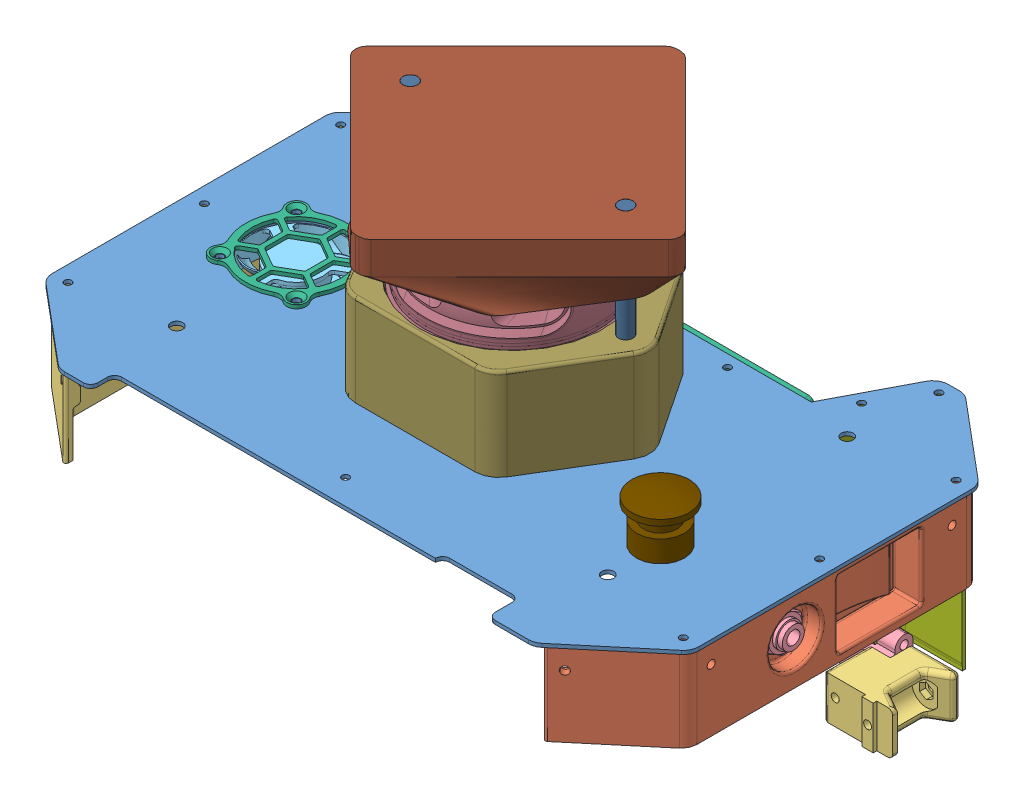
SolidWorks assembly BlocSup, configuration Défaut. Lengths in mm.
Overall size (270 207.07 197.32).
32 component instances, 28 part files, 65 mates.
Components (placement in the parent):
- BlocSup_Plaque-1: BlocSup_Plaque [Défaut] at (0 343.5 0) x (0 0 -1) z (1 0 0) size (180 1.5 270)
- BlocSup_CarterGauche-1: BlocSup_CarterGauche [Défaut] at (135 295.5187 -42.1103) x (0 0 -1) z (1 0 0) size (173.26 35 33.94)
- BlocSup_CarterDroite-1: BlocSup_CarterDroite [Défaut] at (-135 308.5 0) x (0 0 1) z (-1 0 0) size (173.26 35 33.94)
- BlocSup_Charniere-1: BlocSup_Charniere [Défaut] at (0 238 -83.5) x (0 0 -1) z (1 0 0) size (10 17.5 158)
- BlocSup_SupportCharniere-1: BlocSup_SupportCharniere [Défaut] at (-90 227.5 -50) x (-1 0 0) z (0 0 -1) size (29 18 30)
- BlocSup_SupportEcran-1: BlocSup_SupportEcran [Défaut] at (0 292.3655 -56.8959) x (-1 0 0) z (0 0.32983 -0.94404) size (138 106.19 17.63)
- BlocSup_CarterEcran-1: BlocSup_CarterEcran [Défaut] at (70.0918 245.5 -90) x (-1 0 0) z (0 0 -1) size (29.48 98 45)
- _Symétrie_BlocSup_CarterEcran-1: _Symétrie_BlocSup_CarterEcran [Défaut] at (-70.0918 245.5 -90) size (29.48 98 45.96)
- Lidar-1: Lidar [Default] at (0 345 0) size (135.87 85 134.45)
  - Lidar_Base-1: Lidar_Base [Défaut] at origin size (105 35.5 75)
  - Lidar_Tige-1: Lidar_Tige [Défaut] at (-45 5 -2.5) size (6 80 6)
  - Lidar_Tige-2: Lidar_Tige [Défaut] at (45 5 -2.5) size (6 80 6)
  - Lidar_Top-1: Lidar_Top [Défaut] at (0 85 -2.5) x (-1 0 0) z (0 0 1) size (135.87 27.01 134.45)
  - Lidar_Cache-1: Lidar_Cache [Défaut] at (0 38.3 -2.5) x (-1 0 0) z (0 0 1) size (110 38.3 83)
  - rplidar-a2-1: rplidar-a2 [Défaut] at (-75 9.2861 -6.0269) x (0 0 -1) z (1 0 0) size (80.61 40.81 84.84)
- Tirette-1: Tirette [Défaut] at (15.8155 -23.9188 -0.5) size (18.01 65.48 50.46)
  - TiretteDiam6-1: TiretteDiam6 [Default] at (-106.1573 340.7878 -102.5731) x (-0.007647 0.642769 0.766022) z (0 -0.766044 0.642788) size (6 6 61)
  - Tirette_Support-1: Tirette_Support [Défaut] at (-106.1573 276.0497 -60) x (0 0 1) z (-1 0 0) size (28.63 58.34 18.1)
  - microswitchGaletAss-1: microswitchGaletAss [Défaut] at (-106.1573 330.3845 -72.9571) x (0 -0.766044 0.642788) z (1 0 0) size (21.06 21.1 7)
    - microswitchGalet02-1: microswitchGalet02 [Défaut] at origin size (20 15 7)
    - microswitchGalet01-1: microswitchGalet01 [Défaut] at (1.7099 12.1145 0) x (0.996636 -0.081957 0) z (0 0 1) size (19 9 6)
- APEM_A01ES_A0154B-1: APEM_A01ES_A0154B [Défaut] at (90 345 28) size (24 61 24)
- Ecran_5po_DFR0550-1: Ecran_5po_DFR0550 [Default] at (0 297.1481 -70.5845) x (1 0 0) z (0 0.32983 -0.94404) size (121 76 27.3)
- interrupteur principal-1: interrupteur principal [Défaut] at (121.5 326 -20) x (0 0 1) z (0 1 0) size (32 33.35 25)
- _Symétrie_BlocSup_SupportCharniere-3: _Symétrie_BlocSup_SupportCharniere [Défaut] at (90 227.5 -50) size (29 18 30)
- PriseJackAlim-1: PriseJackAlim [Default] at (123.5 326 15) x (0 -1 0) z (0 0 1) size (16.17 25.3 16)
- Ventilo_AAB_Diam40-1: Ventilo_AAB_Diam40 [Défaut] at (-90 333.5 0) x (1 0 0) z (0 1 0) size (45 40 10)
- Ventilo_Cache-1: Ventilo_Cache [Défaut] at (-90 345 0) x (0 0 -1) z (1 0 0) size (42.6 1.5 42.6)
- Raspberry-Pi-4-Model-B-03-1: Raspberry-Pi-4-Model-B-03 [Défaut] at (-32.5 266.2952 -67.1696) x (1 0 0) z (0 -0.32983 0.94404) size (87.94 57.9 19.63)
- InterfaceRaspi-1: InterfaceRaspi [Défaut] at (-107.5 400.9752 -9.9988) x (1 0 0) z (0 -0.32983 0.94404) size (65 56 17.8)
- 4010 - Blower Assembly-1: 4010 - Blower Assembly [Défaut] at (19.1478 275.9461 -78.4041) x (-1 0 0) z (0 -0.32983 0.94404) size (40 40 9.75)
- Ventilo_Raspi_Support-1: Ventilo_Raspi_Support [Défaut] at (0 270.259 -67.9033) x (-1 0 0) z (0 0.94404 0.32983) size (64 15.5 14.5)
Mates (geometry in assembly coordinates):
- Coïncidente93: coincident: plane of assembly; plane of assembly; plane of BlocSup_Plaque-1 through (0 345 0) normal (0 1 0); plane of APEM_A01ES_A0154B-1 through (100 345 28) normal (0 -1 0)
- Coaxiale32: concentric: cylinder of assembly; cylinder of assembly; cylinder of BlocSup_Plaque-1 through (90 343.5 28) axis (0 1 0) radius 8.15; cylinder of APEM_A01ES_A0154B-1 through (90 364 28) axis (0 -1 0) radius 8
- Coïncidente164: coincident: plane of assembly; plane of assembly; plane of BlocSup_Plaque-1 through (0 343.5 0) normal (0 -1 0); plane of BlocSup_CarterEcran-1 through (88.4018 343.5 -90) normal (0 1 0)
- Coïncidente183: coincident: plane of assembly; plane of assembly; plane of BlocSup_Plaque-1 through (135 345 -90) normal (0 0 -1); plane of BlocSup_CarterEcran-1 through (70.0918 245.5 -90) normal (0 0 -1)
- Coïncidente174: coincident: plane of assembly; plane of assembly; plane of BlocSup_Plaque-1 through (0 343.5 0) normal (0 -1 0); plane of BlocSup_CarterGauche-1 through (135 343.5 0) normal (0 1 0)
- Coïncidente178: coincident: plane of assembly; plane of assembly; plane of BlocSup_Plaque-1 through (0 343.5 0) normal (0 -1 0); plane of BlocSup_CarterDroite-1 through (-135 343.5 0) normal (0 1 0)
- Coaxiale43: concentric: cylinder of assembly; cylinder of assembly; cylinder of BlocSup_Charniere-1 through (79 246.75 -84.75) axis (-1 0 0) radius 1.75; cylinder of BlocSup_SupportEcran-1 through (-48.5 246.75 -84.75) axis (1 0 0) radius 1.75
- Largeur9: width: plane of assembly; plane of assembly; plane of assembly; plane of assembly; plane of BlocSup_Charniere-1 through (-15 238 -83.5) normal (-1 0 0); plane of BlocSup_Charniere-1 through (15 238 -83.5) normal (1 0 0); plane of BlocSup_SupportEcran-1 through (-15.5 292.3655 -56.8959) normal (1 0 0); plane of BlocSup_SupportEcran-1 through (15.5 292.3655 -56.8959) normal (-1 0 0)
- Coïncidente176: coincident: plane of assembly; plane of assembly; plane of interrupteur principal-1 through (121.5 326 -20) normal (-1 0 0); plane of BlocSup_CarterGauche-1 through (121.5 295.5187 -42.1103) normal (1 0 0)
- Largeur18: width: plane of assembly; plane of assembly; plane of assembly; plane of assembly; plane of BlocSup_CarterGauche-1 through (121.5 295.5187 -2.5) normal (0 0 -1); plane of BlocSup_CarterGauche-1 through (121.5 295.5187 -37.5) normal (0 0 1); plane of interrupteur principal-1 through (104.5 315 -34.5) normal (0 0 -1); plane of interrupteur principal-1 through (104.5 315 -5.5) normal (0 0 1)
- Largeur19: width: plane of assembly; plane of assembly; plane of assembly; plane of assembly; plane of interrupteur principal-1 through (104.5 337 -34.5) normal (0 1 0); plane of interrupteur principal-1 through (104.5 315 -34.5) normal (0 -1 0); plane of BlocSup_CarterGauche-1 through (121.5 340 -42.1103) normal (0 -1 0); plane of BlocSup_CarterGauche-1 through (121.5 312 -42.1103) normal (0 1 0)
- Coïncidente184: coincident: plane of assembly; plane of assembly; plane of BlocSup_Plaque-1 through (0 343.5 0) normal (0 -1 0); plane of _Symétrie_BlocSup_CarterEcran-1 through (-88.4018 343.5 -90) normal (0 1 0)
- Coaxiale48: concentric: cylinder of assembly; cylinder of assembly; cylinder of BlocSup_Plaque-1 through (-93.3098 343.5 -85) axis (0 1 0) radius 1.5; cylinder of _Symétrie_BlocSup_CarterEcran-1 through (-93.3098 343.5 -85) axis (0 1 0) radius 1.7
- Parallèle2: parallel: plane of assembly; plane of assembly; plane of BlocSup_Plaque-1 through (-135 345 -90) normal (0 0 -1); plane of _Symétrie_BlocSup_CarterEcran-1 through (-70.0918 245.5 -90) normal (0 0 -1)
- Coaxiale51: concentric: cylinder of assembly; cylinder of assembly; cylinder of BlocSup_Plaque-1 through (93.3098 343.5 -85) axis (0 1 0) radius 1.5; cylinder of BlocSup_CarterEcran-1 through (93.3098 343.5 -85) axis (0 1 0) radius 1.7
- Coaxiale52: concentric: cylinder of assembly; cylinder of assembly; cylinder of BlocSup_Plaque-1 through (128.5 343.5 56.969) axis (0 1 0) radius 1.5; cylinder of BlocSup_CarterGauche-1 through (128.5 343.5 56.969) axis (0 1 0) radius 2
- Coaxiale53: concentric: cylinder of assembly; cylinder of assembly; cylinder of BlocSup_Plaque-1 through (128.5 343.5 -56.969) axis (0 1 0) radius 1.5; cylinder of BlocSup_CarterGauche-1 through (128.5 343.5 -56.969) axis (0 1 0) radius 2
- Coaxiale54: concentric: cylinder of assembly; cylinder of assembly; cylinder of BlocSup_Plaque-1 through (-128.5 343.5 56.969) axis (0 1 0) radius 1.5; cylinder of BlocSup_CarterDroite-1 through (-128.5 343.5 56.969) axis (0 1 0) radius 2
- Coaxiale56: concentric: cylinder of assembly; cylinder of assembly; cylinder of BlocSup_Plaque-1 through (-128.5 343.5 -56.969) axis (0 1 0) radius 1.5; cylinder of BlocSup_CarterDroite-1 through (-128.5 343.5 -56.969) axis (0 1 0) radius 2
- Coïncidente186: coincident: plane of assembly; plane of BlocSup_SupportCharniere-1 through (-70 245.5 -60) normal (0 0 1); line of assembly
- Distance26: distance = 1 mm: plane of assembly; line of assembly; plane of BlocSup_SupportCharniere-1 through (-99 245.5 -60) normal (-1 0 0)
- Parallèle3: parallel: plane of assembly through (0 0 0) normal (0 1 0); plane of BlocSup_SupportCharniere-1 through (-90 245.5 -50) normal (0 1 0); plane of assembly
- Coaxiale59: concentric: cylinder of assembly; cylinder of assembly; cylinder of BlocSup_Charniere-1 through (-75 238 -88.5) axis (0 0 -1) radius 1.7; cylinder of BlocSup_SupportCharniere-1 through (-75 238 -78.5) axis (0 0 -1) radius 1.7
- Coaxiale164: concentric: cylinder of assembly; circle of assembly; cylinder of _Symétrie_BlocSup_CarterEcran-1 through (-84.3418 288.5 -90) axis (0 0 -1) radius 1.7; circle of Tirette-1/Tirette_Support-1
- Coaxiale165: concentric: cylinder of assembly; cylinder of assembly; cylinder of _Symétrie_BlocSup_CarterEcran-1 through (-96.3418 288.5 -90) axis (0 0 -1) radius 1.7; cylinder of Tirette-1/Tirette_Support-1 through (-96.3418 288.5 -88.5) axis (0 0 -1) radius 1.25
- Coïncidente503: coincident: plane of assembly; plane of assembly; plane of _Symétrie_BlocSup_CarterEcran-1 through (-70.0918 245.5 -88.5) normal (0 0 1); plane of Tirette-1/Tirette_Support-1 through (-99.3418 313.503 -88.5) normal (0 0 -1)
- Coaxiale166: concentric: cylinder of assembly; cylinder of assembly; cylinder of BlocSup_CarterGauche-1 through (99.5628 326 15) axis (1 0 0) radius 5.75; cylinder of PriseJackAlim-1 through (123.5 326 15) axis (-1 0 0) radius 5.4
- Coïncidente504: coincident: plane of assembly; plane of assembly; plane of BlocSup_CarterGauche-1 through (123.5 295.5187 -42.1103) normal (-1 0 0); plane of PriseJackAlim-1 through (123.5 320.6 15) normal (1 0 0)
- Coïncidente508: coincident: plane of assembly; plane of assembly; plane of BlocSup_Plaque-1 through (0 343.5 0) normal (0 -1 0); plane of Ventilo_AAB_Diam40-1 through (-90 343.5 0) normal (0 1 0)
- Coaxiale172: concentric: circle of assembly; circle of assembly; circle of BlocSup_Plaque-1; circle of Ventilo_AAB_Diam40-1
- Coaxiale173: concentric: circle of assembly; circle of assembly; circle of BlocSup_Plaque-1; circle of Ventilo_AAB_Diam40-1
- Coïncidente511: coincident: plane of assembly; plane of assembly; plane of BlocSup_Plaque-1 through (0 345 0) normal (0 1 0); plane of Ventilo_Cache-1 through (-90 345 0) normal (0 -1 0)
- Coaxiale176: concentric: circle of BlocSup_Plaque-1; circle of Ventilo_Cache-1
- Coaxiale177: concentric: circle of BlocSup_Plaque-1; circle of Ventilo_Cache-1
- Coïncidente512: coincident: plane of assembly; plane of assembly; plane of BlocSup_Charniere-1 through (79 243 -78.5) normal (0 0 1); plane of _Symétrie_BlocSup_SupportCharniere-3 through (70 245.5 -78.5) normal (0 0 -1)
- Distance27: distance = 98 mm: plane of assembly; plane of assembly; plane of _Symétrie_BlocSup_SupportCharniere-3 through (90 245.5 -50) normal (0 1 0); plane of BlocSup_Plaque-1 through (0 343.5 0) normal (0 -1 0)
- Parallèle4: parallel: plane of assembly through (0 0 0) normal (0 1 0); plane of BlocSup_Charniere-1 through (79 233 -78.5) normal (0 -1 0); plane of assembly
- Coïncidente513: coincident: plane of ? through (25.4 271.288 -63.3173) normal (0 -0.331076 0.943604); unknown of ?
- Coaxiale178: concentric: circle of ?; cylinder of ? through (29 266.8598 -58.2475) axis (0 -0.331076 0.943604) radius 1.6
- Coaxiale179: concentric: cylinder of ? through (-29 269.8722 -66.8334) axis (0 -0.331076 0.943604) radius 1.25; cylinder of ? through (-29 266.8598 -58.2475) axis (0 -0.331076 0.943604) radius 1.6
- Coïncidente515: coincident: plane of ? through (-25.395 255.7041 -116.3899) normal (0 -0.992519 0.122088); plane of ? through (25.4 255.7066 -116.37) normal (0 0.992519 -0.122088)
- Coaxiale182: concentric: circle of ?; circle of ?
- Coaxiale183: concentric: circle of ?; circle of ?
- Coïncidente520: coincident: plane of ? through (-49.5 247.492 -162.6735) normal (0 0.992519 -0.122088); plane of ? through (49 248.3466 -155.7259) normal (0 -0.992519 0.122088)
- Coaxiale184: concentric: circle of ?; cylinder of ? through (-29 263.8168 -162.6893) axis (0 -0.998129 0.06114) radius 1.75
- Parallèle5: parallel: plane of ? through (29 256.6043 -166.817) normal (0 -0.122088 -0.992519); plane of ? through (33 258.5894 -167.0612) normal (0 0.122088 0.992519)
- Coïncidente522: coincident: plane of ? through (49 262.7878 -157.5023) normal (0 -0.992519 0.122088); plane of ? through (49 262.7878 -157.5023) normal (0 0.992519 -0.122088)
- Coaxiale185: concentric: cylinder of ? through (65 264.7412 -141.622) axis (0 0.992519 -0.122088) radius 1.5; cylinder of ? through (65 264.7412 -141.622) axis (0 -0.992519 0.122088) radius 1.25
- Coaxiale186: concentric: cylinder of ? through (65 260.8344 -173.3826) axis (0 0.992519 -0.122088) radius 1.5; cylinder of ? through (65 260.8344 -173.3826) axis (0 -0.992519 0.122088) radius 1.25
- Coïncidente524: coincident: plane of assembly; plane of assembly; plane of Raspberry-Pi-4-Model-B-03-1 through (-25.4 312.6349 -48.3312) normal (0 -0.32983 0.94404); plane of InterfaceRaspi-1 through (25.395 312.616 -48.3378) normal (0 0.32983 -0.94404)
- Coïncidente528: coincident: plane of assembly; plane of assembly; plane of BlocSup_SupportEcran-1 through (0 293.0252 -58.784) normal (0 0.32983 -0.94404); plane of Ecran_5po_DFR0550-1 through (56.5 260.9278 -69.9982) normal (0 -0.32983 0.94404)
- Coaxiale191: concentric: cylinder of BlocSup_SupportEcran-1 through (56.5 260.2678 -68.1092) axis (0 0.32983 -0.94404) radius 1.5; cylinder of Ecran_5po_DFR0550-1 through (56.5 260.9278 -69.9982) axis (0 0.32983 -0.94404) radius 1.25
- Coaxiale192: concentric: cylinder of BlocSup_SupportEcran-1 through (-56.5 260.2678 -68.1092) axis (0 0.32983 -0.94404) radius 1.5; cylinder of Ecran_5po_DFR0550-1 through (-56.5 260.9278 -69.9982) axis (0 0.32983 -0.94404) radius 1.25
- Coïncidente529: coincident: plane of Ecran_5po_DFR0550-1 through (-29 269.8962 -66.8648) normal (0 -0.32983 0.94404); plane of Raspberry-Pi-4-Model-B-03-1 through (-32.5 266.5921 -68.0192) normal (0 0.32983 -0.94404)
- Coaxiale193: concentric: cylinder of Ecran_5po_DFR0550-1 through (29 269.8962 -66.8648) axis (0 0.32983 -0.94404) radius 1.25; cylinder of Raspberry-Pi-4-Model-B-03-1 through (29 269.9292 -66.9592) axis (0 -0.32983 0.94404) radius 1.35
- Coaxiale194: concentric: cylinder of Ecran_5po_DFR0550-1 through (-29 269.8962 -66.8648) axis (0 0.32983 -0.94404) radius 1.25; cylinder of Raspberry-Pi-4-Model-B-03-1 through (-29 269.9292 -66.9592) axis (0 -0.32983 0.94404) radius 1.35
- Parallèle6: parallel: plane of Raspberry-Pi-4-Model-B-03-1 through (-25.4 312.6349 -48.3312) normal (0 -0.32983 0.94404); plane of InterfaceRaspi-1 through (25.395 312.616 -48.3378) normal (0 0.32983 -0.94404)
- Coaxiale195: concentric: cylinder of Raspberry-Pi-4-Model-B-03-1 through (-29 316.1872 -50.7976) axis (0 -0.32983 0.94404) radius 1.35; cylinder of InterfaceRaspi-1 through (-29 312.9713 -41.5932) axis (0 -0.32983 0.94404) radius 1.6
- Coaxiale196: concentric: cylinder of Raspberry-Pi-4-Model-B-03-1 through (29 316.1872 -50.7976) axis (0 -0.32983 0.94404) radius 1.35; cylinder of InterfaceRaspi-1 through (29 312.9713 -41.5932) axis (0 -0.32983 0.94404) radius 1.6
- Coïncidente534: coincident: plane of Raspberry-Pi-4-Model-B-03-1 through (49.5 269.1273 -66.1801) normal (0 -0.32983 0.94404); plane of Ventilo_Raspi_Support-1 through (0 269.5993 -66.0152) normal (0 0.32983 -0.94404)
- Coïncidente535: coincident: plane of assembly; plane of assembly; plane of 4010 - Blower Assembly-1 through (-2.4406 260.6141 -56.9728) normal (0 0.94404 0.32983); plane of Ventilo_Raspi_Support-1 through (22.5 259.9544 -55.0847) normal (0 0.94404 0.32983)
- Coaxiale199: concentric: cylinder of Ecran_5po_DFR0550-1 through (29 269.8962 -66.8648) axis (0 0.32983 -0.94404) radius 1.25; cylinder of Ventilo_Raspi_Support-1 through (29 265.1466 -53.2707) axis (0 0.32983 -0.94404) radius 1.6
- Coaxiale200: concentric: cylinder of Ecran_5po_DFR0550-1 through (-29 269.8962 -66.8648) axis (0 0.32983 -0.94404) radius 1.25; cylinder of Ventilo_Raspi_Support-1 through (-29 265.1466 -53.2707) axis (0 0.32983 -0.94404) radius 1.6
- Coaxiale201: concentric: cylinder of 4010 - Blower Assembly-1 through (-19.9406 260.3979 -63.9336) axis (0 0.32983 -0.94404) radius 1.25; cylinder of Ventilo_Raspi_Support-1 through (-19.9406 262.7067 -70.5419) axis (0 -0.32983 0.94404) radius 1.25
- Coïncidente536: coincident: plane of 4010 - Blower Assembly-1 through (-2.4406 245.0316 -73.0098) normal (0 0.32983 -0.94404); plane of Ventilo_Raspi_Support-1 through (-22.6906 271.9367 -63.6097) normal (0 -0.32983 0.94404)
